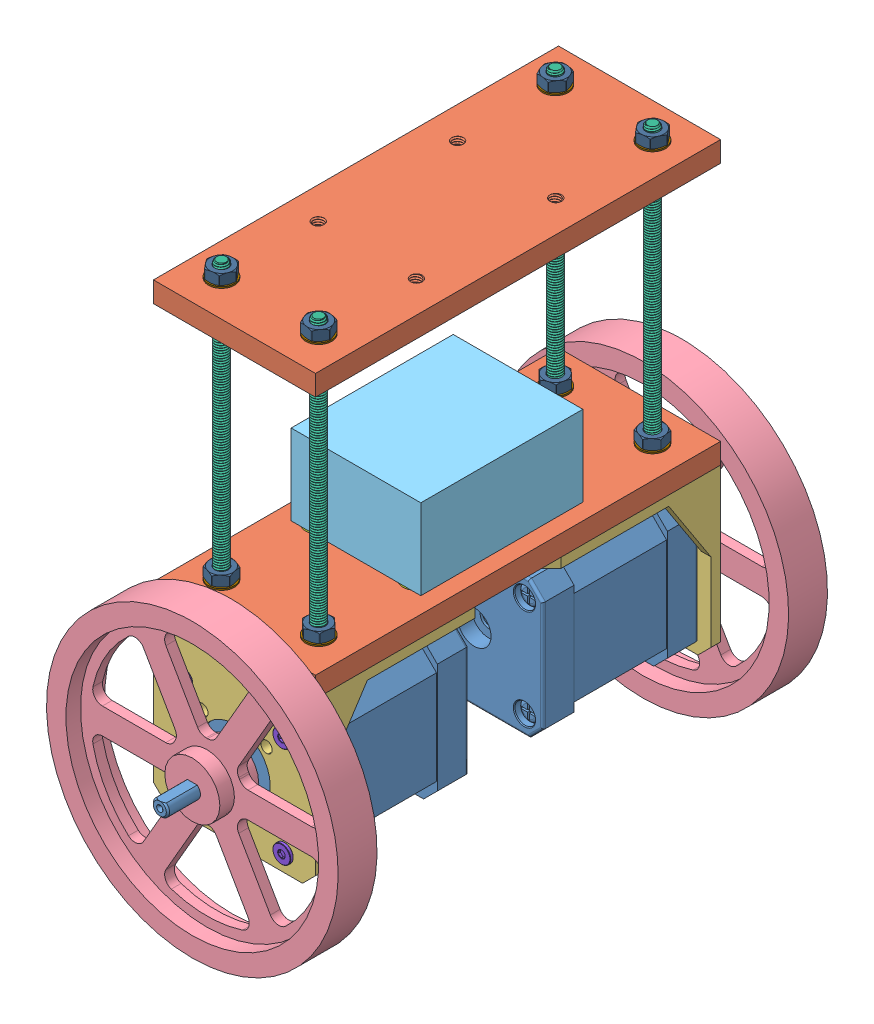
SolidWorks assembly robot, configuration Default. Lengths in mm.
Overall size (90 167.6 171.06).
65 component instances, 10 part files, 39 mates.
Components (placement in the parent):
- 6627T91_Stepper Motor-1: 6627T91_Stepper Motor [6627T91] at (0 -33.425 48.513) size (42.4 43.16 74.04)
- 6627T91_Stepper Motor-2: 6627T91_Stepper Motor [6627T91] at (0 -33.425 -48.513) x (-1 0 0) z (0 0 -1) size (42.4 43.16 74.04)
- 2726N61_Medium Density Fiberboard Sheet-2: 2726N61_Medium Density Fiberboard Sheet [2726N61] at origin size (50 6.96 125)
- 2726N61_Medium Density Fiberboard Sheet-7: 2726N61_Medium Density Fiberboard Sheet [top] at (0 80.65 0) x (-1 0 0) z (0 0 1) size (50 6.96 125)
- bracket-1: bracket [Default] at (0 -3.175 62.5) x (-1 0 0) z (0 0 1) size (50 51.25 53.25)
- bracket-2: bracket [Default] at (0 -3.175 -62.5) x (1 0 0) z (0 0 -1) size (50 51.25 53.25)
- wheel-1: wheel [Default] at (0 -33.425 69.5) x (0 1 0) z (0 0 1) size (90 90 12)
- wheel-2: wheel [Default] at (0 -33.425 -69.5) x (0 1 0) z (0 0 1) size (90 90 12)
- battery-2: battery [Default] at origin size (40 25 50)
- 98861A050_Low-Strength Steel Threaded Rod-1: 98861A050_Low-Strength Steel Threaded Rod [98861A050] at (-15 38.825 51.5) x (0 0 1) z (0 1 0) size (4.62 4.16 100.76)
- 98861A050_Low-Strength Steel Threaded Rod-3: 98861A050_Low-Strength Steel Threaded Rod [98861A050] at (-14.9508 38.825 -51.5) x (0 0 -1) z (0 1 0) size (4.62 4.16 100.76)
- 98861A050_Low-Strength Steel Threaded Rod-2: 98861A050_Low-Strength Steel Threaded Rod [98861A050] at (14.9508 38.825 51.5) x (0 0 1) z (0 1 0) size (4.62 4.16 100.76)
- 98861A050_Low-Strength Steel Threaded Rod-4: 98861A050_Low-Strength Steel Threaded Rod [98861A050] at (15 38.825 -51.5) x (0 0 -1) z (0 1 0) size (4.62 4.16 100.76)
- 92125A104_18-8 Stainless Steel Hex Drive Flat Head Screw-2: 92125A104_18-8 Stainless Steel Hex Drive Flat Head Screw [92125A104] at (-15 -5.475 21.5) x (1 0 0) z (0 1 0) size (8 8 15.24)
- 90358A117_Ultra-Low-Profile Socket Head Screw-1: 90358A117_Ultra-Low-Profile Socket Head Screw [90358A117] at (15.5 -17.925 59.5) x (-0.669992 0.742368 0) z (0 0 -1) size (5.5 5.5 8.29)
- 98689A113_General Purpose 18-8 Stainless Steel Washer-5: 98689A113_General Purpose 18-8 Stainless Steel Washer [98689A113] at (-15 -6.425 21.5) x (0.781875 0 -0.623435) z (0 -1 0) size (8 8 0.5)
- 98689A113_General Purpose 18-8 Stainless Steel Washer-9: 98689A113_General Purpose 18-8 Stainless Steel Washer [98689A113] at (-15 -6.425 51.5) x (0.571369 0 -0.820693) z (0 1 0) size (8 8 0.5)
- 98689A113_General Purpose 18-8 Stainless Steel Washer-17: 98689A113_General Purpose 18-8 Stainless Steel Washer [98689A113] at (-15 84.075 51.5) x (-0.71978 0 -0.694202) z (0 -1 0) size (8 8 0.5)
- 98689A113_General Purpose 18-8 Stainless Steel Washer-19: 98689A113_General Purpose 18-8 Stainless Steel Washer [98689A113] at (-15 77.225 51.5) x (-0.571128 0 0.820861) z (0 -1 0) size (8 8 0.5)
- 98689A113_General Purpose 18-8 Stainless Steel Washer-26: 98689A113_General Purpose 18-8 Stainless Steel Washer [98689A113] at (15 3.425 51.5) x (0.999996 0 -0.002696) z (0 1 0) size (8 8 0.5)
- 90592A011_Steel Hex Nut-1: 90592A011_Steel Hex Nut [90592A011] at (-15 -8.275 21.5) x (0.963211 0 0.268748) z (0 -1 0) size (7 8.03 3.62)
- 90592A011_Steel Hex Nut-5: 90592A011_Steel Hex Nut [90592A011] at (-15 -8.275 51.5) x (0.976506 0 0.215491) z (0 -1 0) size (7 8.03 3.62)
- 90592A011_Steel Hex Nut-13: 90592A011_Steel Hex Nut [90592A011] at (-15 85.925 51.5) x (0.139683 0 0.990196) z (0 1 0) size (7 8.03 3.62)
- 90592A011_Steel Hex Nut-15: 90592A011_Steel Hex Nut [90592A011] at (-15 75.375 51.5) x (1 0 0) z (0 1 0) size (7 8.03 3.62)
- 90592A011_Steel Hex Nut-22: 90592A011_Steel Hex Nut [90592A011] at (15 5.275 51.5) x (0.976506 0 0.215491) z (0 -1 0) size (7 8.03 3.62)
- 98689A113_General Purpose 18-8 Stainless Steel Washer-6: 98689A113_General Purpose 18-8 Stainless Steel Washer [98689A113] at (15 -6.425 21.5) x (0.781875 0 0.623435) z (0 -1 0) size (8 8 0.5)
- 90592A011_Steel Hex Nut-23: 90592A011_Steel Hex Nut [90592A011] at (15 -8.275 21.5) x (-0.963211 0 0.268748) z (0 -1 0) size (7 8.03 3.62)
- 90592A011_Steel Hex Nut-28: 90592A011_Steel Hex Nut [90592A011] at (-15 -8.275 -21.5) x (0.963211 0 -0.268748) z (0 -1 0) size (7 8.03 3.62)
- 98689A113_General Purpose 18-8 Stainless Steel Washer-7: 98689A113_General Purpose 18-8 Stainless Steel Washer [98689A113] at (-15 -6.425 -21.5) x (-0.781875 0 -0.623435) z (0 -1 0) size (8 8 0.5)
- 90592A011_Steel Hex Nut-29: 90592A011_Steel Hex Nut [90592A011] at (15 -8.275 -21.5) x (-0.963211 0 -0.268748) z (0 -1 0) size (7 8.03 3.62)
- 98689A113_General Purpose 18-8 Stainless Steel Washer-8: 98689A113_General Purpose 18-8 Stainless Steel Washer [98689A113] at (15 -6.425 -21.5) x (-0.781875 0 0.623435) z (0 -1 0) size (8 8 0.5)
- 98689A113_General Purpose 18-8 Stainless Steel Washer-10: 98689A113_General Purpose 18-8 Stainless Steel Washer [98689A113] at (15 -6.425 51.5) x (0.571369 0 0.820693) z (0 1 0) size (8 8 0.5)
- 90592A011_Steel Hex Nut-24: 90592A011_Steel Hex Nut [90592A011] at (15 -8.275 51.5) x (-0.976506 0 0.215491) z (0 -1 0) size (7 8.03 3.62)
- 98689A113_General Purpose 18-8 Stainless Steel Washer-11: 98689A113_General Purpose 18-8 Stainless Steel Washer [98689A113] at (-15 -6.425 -51.5) x (-0.571369 0 -0.820693) z (0 1 0) size (8 8 0.5)
- 90592A011_Steel Hex Nut-30: 90592A011_Steel Hex Nut [90592A011] at (-15 -8.275 -51.5) x (0.976506 0 -0.215491) z (0 -1 0) size (7 8.03 3.62)
- 98689A113_General Purpose 18-8 Stainless Steel Washer-12: 98689A113_General Purpose 18-8 Stainless Steel Washer [98689A113] at (15 -6.425 -51.5) x (-0.571369 0 0.820693) z (0 1 0) size (8 8 0.5)
- 90592A011_Steel Hex Nut-31: 90592A011_Steel Hex Nut [90592A011] at (15 -8.275 -51.5) x (-0.976506 0 -0.215491) z (0 -1 0) size (7 8.03 3.62)
- 90592A011_Steel Hex Nut-25: 90592A011_Steel Hex Nut [90592A011] at (15 75.375 51.5) x (-1 0 0) z (0 1 0) size (7 8.03 3.62)
- 90592A011_Steel Hex Nut-26: 90592A011_Steel Hex Nut [90592A011] at (15 85.925 51.5) x (-0.139683 0 0.990196) z (0 1 0) size (7 8.03 3.62)
- 98689A113_General Purpose 18-8 Stainless Steel Washer-20: 98689A113_General Purpose 18-8 Stainless Steel Washer [98689A113] at (15 84.075 51.5) x (-0.71978 0 0.694202) z (0 -1 0) size (8 8 0.5)
- 98689A113_General Purpose 18-8 Stainless Steel Washer-21: 98689A113_General Purpose 18-8 Stainless Steel Washer [98689A113] at (15 77.225 51.5) x (-0.571128 0 -0.820861) z (0 -1 0) size (8 8 0.5)
- 90592A011_Steel Hex Nut-32: 90592A011_Steel Hex Nut [90592A011] at (15 75.375 -51.5) x (-1 0 0) z (0 1 0) size (7 8.03 3.62)
- 90592A011_Steel Hex Nut-33: 90592A011_Steel Hex Nut [90592A011] at (15 85.925 -51.5) x (-0.139683 0 -0.990196) z (0 1 0) size (7 8.03 3.62)
- 98689A113_General Purpose 18-8 Stainless Steel Washer-22: 98689A113_General Purpose 18-8 Stainless Steel Washer [98689A113] at (15 84.075 -51.5) x (0.71978 0 0.694202) z (0 -1 0) size (8 8 0.5)
- 90592A011_Steel Hex Nut-34: 90592A011_Steel Hex Nut [90592A011] at (-15 85.925 -51.5) x (0.139683 0 -0.990196) z (0 1 0) size (7 8.03 3.62)
- 98689A113_General Purpose 18-8 Stainless Steel Washer-23: 98689A113_General Purpose 18-8 Stainless Steel Washer [98689A113] at (-15 84.075 -51.5) x (0.71978 0 -0.694202) z (0 -1 0) size (8 8 0.5)
- 90592A011_Steel Hex Nut-35: 90592A011_Steel Hex Nut [90592A011] at (-15 75.375 -51.5) x (1 0 0) z (0 1 0) size (7 8.03 3.62)
- 98689A113_General Purpose 18-8 Stainless Steel Washer-24: 98689A113_General Purpose 18-8 Stainless Steel Washer [98689A113] at (-15 77.225 -51.5) x (0.571128 0 0.820861) z (0 -1 0) size (8 8 0.5)
- 98689A113_General Purpose 18-8 Stainless Steel Washer-25: 98689A113_General Purpose 18-8 Stainless Steel Washer [98689A113] at (15 77.225 -51.5) x (0.571128 0 -0.820861) z (0 -1 0) size (8 8 0.5)
- 90358A117_Ultra-Low-Profile Socket Head Screw-2: 90358A117_Ultra-Low-Profile Socket Head Screw [90358A117] at (15.5 -48.925 59.5) x (-0.669992 -0.742368 0) z (0 0 -1) size (5.5 5.5 8.29)
- 90358A117_Ultra-Low-Profile Socket Head Screw-3: 90358A117_Ultra-Low-Profile Socket Head Screw [90358A117] at (-15.5 -17.925 59.5) x (0.669992 0.742368 0) z (0 0 -1) size (5.5 5.5 8.29)
- 90358A117_Ultra-Low-Profile Socket Head Screw-4: 90358A117_Ultra-Low-Profile Socket Head Screw [90358A117] at (-15.5 -48.925 59.5) x (0.669992 -0.742368 0) z (0 0 -1) size (5.5 5.5 8.29)
- 90358A117_Ultra-Low-Profile Socket Head Screw-5: 90358A117_Ultra-Low-Profile Socket Head Screw [90358A117] at (15.5 -17.925 -59.5) x (-0.669992 0.742368 0) z (0 0 1) size (5.5 5.5 8.29)
- 90358A117_Ultra-Low-Profile Socket Head Screw-6: 90358A117_Ultra-Low-Profile Socket Head Screw [90358A117] at (15.5 -48.925 -59.5) x (-0.669992 -0.742368 0) z (0 0 1) size (5.5 5.5 8.29)
- 90358A117_Ultra-Low-Profile Socket Head Screw-7: 90358A117_Ultra-Low-Profile Socket Head Screw [90358A117] at (-15.5 -48.925 -59.5) x (0.669992 -0.742368 0) z (0 0 1) size (5.5 5.5 8.29)
- 90358A117_Ultra-Low-Profile Socket Head Screw-8: 90358A117_Ultra-Low-Profile Socket Head Screw [90358A117] at (-15.5 -17.925 -59.5) x (0.669992 0.742368 0) z (0 0 1) size (5.5 5.5 8.29)
- 98689A113_General Purpose 18-8 Stainless Steel Washer-27: 98689A113_General Purpose 18-8 Stainless Steel Washer [98689A113] at (-15 3.425 51.5) x (0.999996 0 0.002696) z (0 1 0) size (8 8 0.5)
- 90592A011_Steel Hex Nut-27: 90592A011_Steel Hex Nut [90592A011] at (-15 5.2763 51.5) x (-0.976506 0 0.215491) z (0 1 0) size (7 8.03 3.62)
- 98689A113_General Purpose 18-8 Stainless Steel Washer-28: 98689A113_General Purpose 18-8 Stainless Steel Washer [98689A113] at (15 3.425 -51.5) x (-0.999996 0 -0.002696) z (0 1 0) size (8 8 0.5)
- 90592A011_Steel Hex Nut-36: 90592A011_Steel Hex Nut [90592A011] at (15 5.2763 -51.5) x (0.976506 0 -0.215491) z (0 1 0) size (7 8.03 3.62)
- 90592A011_Steel Hex Nut-37: 90592A011_Steel Hex Nut [90592A011] at (-15 5.275 -51.5) x (-0.976506 0 -0.215491) z (0 -1 0) size (7 8.03 3.62)
- 98689A113_General Purpose 18-8 Stainless Steel Washer-29: 98689A113_General Purpose 18-8 Stainless Steel Washer [98689A113] at (-15 3.425 -51.5) x (-0.999996 0 0.002696) z (0 1 0) size (8 8 0.5)
- 92125A104_18-8 Stainless Steel Hex Drive Flat Head Screw-12: 92125A104_18-8 Stainless Steel Hex Drive Flat Head Screw [92125A104] at (15 -5.475 21.5) x (-1 0 0) z (0 1 0) size (8 8 15.24)
- 92125A104_18-8 Stainless Steel Hex Drive Flat Head Screw-13: 92125A104_18-8 Stainless Steel Hex Drive Flat Head Screw [92125A104] at (-15 -5.475 -21.5) x (1 0 0) z (0 1 0) size (8 8 15.24)
- 92125A104_18-8 Stainless Steel Hex Drive Flat Head Screw-14: 92125A104_18-8 Stainless Steel Hex Drive Flat Head Screw [92125A104] at (15 -5.475 -21.5) x (-1 0 0) z (0 1 0) size (8 8 15.24)
Mates (geometry in assembly coordinates):
- Coincident3: coincident aligned: plane of 6627T91_Stepper Motor-1 through (0 -33.425 48.513) normal (1 0 0)
- Coincident5: coincident aligned: plane of 2726N61_Medium Density Fiberboard Sheet-2 through (-25 -3.175 62.5) normal (0 0 1); plane of bracket-1 through (-25 -54.425 62.5) normal (0 0 1)
- Coincident6: coincident aligned: plane of bracket-1 through (0 -3.175 62.5) normal (0 -1 0); plane of 2726N61_Medium Density Fiberboard Sheet-2 through (152.4 -3.175 152.4) normal (0 -1 0)
- Coincident7: coincident anti-aligned: plane of bracket-1 through (0 -3.175 62.5) normal (-1 0 0)
- Concentric1: concentric anti-aligned: cylinder of 6627T91_Stepper Motor-1 through (0 -33.425 61.532) axis (0 0 -1) radius 10.985; cylinder of bracket-1 through (0 -33.425 9.25) axis (0 0 1) radius 11.05
- Coincident8: coincident anti-aligned: plane of 6627T91_Stepper Motor-1 through (0 -33.425 59.5) normal (0 0 1); plane of bracket-1 through (-25 -54.425 59.5) normal (0 0 -1)
- Concentric2: concentric aligned: cylinder of 6627T91_Stepper Motor-1 through (0 -33.425 85.532) axis (0 0 -1) radius 2.5; cylinder of wheel-1 through (0 -33.425 75.5) axis (0 0 -1) radius 2.5
- Parallel1: parallel anti-aligned: plane of 6627T91_Stepper Motor-1 through (-21.2 -31.433 85.532) normal (0 1 0); plane of wheel-1 through (0 -31.425 75.5) normal (0 -1 0)
- Distance2: distance = 1 mm anti-aligned: plane of bracket-1 through (-25 -54.425 62.5) normal (0 0 1); plane of wheel-1 through (0 -33.425 63.5) normal (0 0 -1)
- Symmetric2: symmetric aligned: plane of bracket-1 through (-17.1 -54.425 21.5) normal (1 0 0); plane of 92125A104_18-8 Stainless Steel Hex Drive Flat Head Screw-2 through (-12.9 -54.425 21.5) normal (-1 0 0); plane of bracket-1 through (-15 -5.475 21.5) normal (1 0 0)
- Concentric4: concentric anti-aligned: cylinder of 90592A011_Steel Hex Nut-1 through (-15 -15.5319 21.5) axis (0 1 0) radius 2; cylinder of 92125A104_18-8 Stainless Steel Hex Drive Flat Head Screw-2 through (-15 -11.825 21.5) axis (0 -1 0) radius 2
- Concentric5: concentric aligned: cylinder of 98689A113_General Purpose 18-8 Stainless Steel Washer-5 through (-15 -6.675 21.5) axis (0 -1 0) radius 2.15; cylinder of 92125A104_18-8 Stainless Steel Hex Drive Flat Head Screw-2 through (-15 -11.825 21.5) axis (0 -1 0) radius 2
- Coincident25: coincident anti-aligned: plane of bracket-1 through (-25 -6.175 62.5) normal (0 -1 0); plane of 98689A113_General Purpose 18-8 Stainless Steel Washer-5 through (-13.6596 -6.175 23.181) normal (0 1 0)
- Tangent3: tangent anti-aligned: plane of bracket-1 through (-25 -6.175 62.5) normal (0 -1 0); torus of 98689A113_General Purpose 18-8 Stainless Steel Washer-9
- Coincident15: coincident anti-aligned: plane of 98689A113_General Purpose 18-8 Stainless Steel Washer-9 through (-16.7645 -6.675 50.2716) normal (0 -1 0); plane of 90592A011_Steel Hex Nut-5 through (-15 -6.675 51.5) normal (0 1 0)
- Coincident16: coincident aligned: plane of 2726N61_Medium Density Fiberboard Sheet-7 through (0 80.65 0) normal (0 0 1)
- Coincident17: coincident anti-aligned: plane of 2726N61_Medium Density Fiberboard Sheet-7 through (0 80.65 0) normal (-1 0 0)
- Tangent4: tangent anti-aligned: plane of 2726N61_Medium Density Fiberboard Sheet-7 through (-152.4 83.825 152.4) normal (0 1 0); torus of 98689A113_General Purpose 18-8 Stainless Steel Washer-17
- Coincident18: coincident anti-aligned: plane of 90592A011_Steel Hex Nut-13 through (-15 84.325 51.5) normal (0 -1 0); plane of 98689A113_General Purpose 18-8 Stainless Steel Washer-17 through (-13.5075 84.325 49.9525) normal (0 1 0)
- Coincident19: coincident anti-aligned: plane of 2726N61_Medium Density Fiberboard Sheet-7 through (-152.4 77.475 152.4) normal (0 -1 0); plane of 98689A113_General Purpose 18-8 Stainless Steel Washer-19 through (-16.7649 77.475 50.2721) normal (0 1 0)
- Tangent5: tangent anti-aligned: torus of 98689A113_General Purpose 18-8 Stainless Steel Washer-19; plane of 90592A011_Steel Hex Nut-15 through (-15 76.975 51.5) normal (0 1 0)
- Coincident20: coincident anti-aligned: plane of 2726N61_Medium Density Fiberboard Sheet-2 through (152.4 3.175 152.4) normal (0 1 0); circle of 92125A104_18-8 Stainless Steel Hex Drive Flat Head Screw-2
- Concentric13: concentric aligned: cylinder of bracket-1 through (15.5 -17.925 9.25) axis (0 0 1) radius 1.75; cylinder of 90358A117_Ultra-Low-Profile Socket Head Screw-1 through (15.5 -17.925 55.5) axis (0 0 1) radius 1.5
- Coincident21: coincident anti-aligned: plane of bracket-1 through (-25 -54.425 62.5) normal (0 0 1); plane of 90358A117_Ultra-Low-Profile Socket Head Screw-1 through (13.7413 -15.9763 62.5) normal (0 0 -1)
- Coincident22: coincident anti-aligned: plane of 2726N61_Medium Density Fiberboard Sheet-2 through (152.4 3.175 152.4) normal (0 1 0); plane of 98689A113_General Purpose 18-8 Stainless Steel Washer-26 through (14.9942 3.175 49.35) normal (0 -1 0)
- Tangent7: tangent anti-aligned: torus of 98689A113_General Purpose 18-8 Stainless Steel Washer-26; plane of 90592A011_Steel Hex Nut-22 through (15 3.675 51.5) normal (0 -1 0)
- Symmetric3: symmetric aligned: plane of bracket-1 through (-12.9 -54.425 21.5) normal (-1 0 0); plane of 98861A050_Low-Strength Steel Threaded Rod-1 through (-17.1 -54.425 21.5) normal (1 0 0); plane of bracket-1 through (-15 38.825 51.5) normal (1 0 0)
- Concentric16: concentric anti-aligned: cylinder of bracket-1 through (-15 -54.425 51.5) axis (0 1 0) radius 2.1; cylinder of 98861A050_Low-Strength Steel Threaded Rod-1 through (-15 -11.175 51.5) axis (0 -1 0) radius 2
- Distance3: distance = 5 mm aligned: plane of 98861A050_Low-Strength Steel Threaded Rod-1 through (-15 -11.175 51.5) normal (0 -1 0); plane of bracket-1 through (-25 -6.175 62.5) normal (0 -1 0)
- Distance4: distance = 5 mm aligned: plane of 2726N61_Medium Density Fiberboard Sheet-7 through (-152.4 83.825 152.4) normal (0 1 0); plane of 98861A050_Low-Strength Steel Threaded Rod-1 through (-15 88.825 51.5) normal (0 1 0)
- Concentric17: concentric aligned: cylinder of 98861A050_Low-Strength Steel Threaded Rod-1 through (-15 -11.175 51.5) axis (0 -1 0) radius 2; cylinder of 90592A011_Steel Hex Nut-13 through (-15 93.1819 51.5) axis (0 -1 0) radius 2
- Concentric18: concentric aligned: cylinder of 98861A050_Low-Strength Steel Threaded Rod-1 through (-15 -11.175 51.5) axis (0 -1 0) radius 2; cylinder of 98689A113_General Purpose 18-8 Stainless Steel Washer-17 through (-15 83.825 51.5) axis (0 -1 0) radius 2.15
- Concentric19: concentric aligned: cylinder of 98861A050_Low-Strength Steel Threaded Rod-1 through (-15 -11.175 51.5) axis (0 -1 0) radius 2; cylinder of 98689A113_General Purpose 18-8 Stainless Steel Washer-19 through (-15 76.975 51.5) axis (0 -1 0) radius 2.15
- Concentric20: concentric aligned: cylinder of 98861A050_Low-Strength Steel Threaded Rod-1 through (-15 -11.175 51.5) axis (0 -1 0) radius 2; cylinder of 90592A011_Steel Hex Nut-15 through (-15 82.6319 51.5) axis (0 -1 0) radius 2
- Concentric21: concentric anti-aligned: cylinder of 98861A050_Low-Strength Steel Threaded Rod-1 through (-15 -11.175 51.5) axis (0 -1 0) radius 2; cylinder of 98689A113_General Purpose 18-8 Stainless Steel Washer-9 through (-15 -6.175 51.5) axis (0 1 0) radius 2.15
- Concentric22: concentric anti-aligned: cylinder of 98861A050_Low-Strength Steel Threaded Rod-1 through (-15 -11.175 51.5) axis (0 -1 0) radius 2; cylinder of 90592A011_Steel Hex Nut-5 through (-15 -15.5319 51.5) axis (0 1 0) radius 2
- Concentric24: concentric anti-aligned: cylinder of bracket-1 through (-15 -54.425 21.5) axis (0 1 0) radius 2.1; cylinder of 92125A104_18-8 Stainless Steel Hex Drive Flat Head Screw-2 through (-15 -11.825 21.5) axis (0 -1 0) radius 2
- Tangent9: tangent anti-aligned: torus of 98689A113_General Purpose 18-8 Stainless Steel Washer-5; plane of 90592A011_Steel Hex Nut-1 through (-15 -6.675 21.5) normal (0 1 0)
- Coincident26: coincident anti-aligned: plane of bracket-1 through (-25 -54.425 62.5) normal (0 0 1); plane of 90358A117_Ultra-Low-Profile Socket Head Screw-1 through (13.7413 -15.9763 62.5) normal (0 0 -1)
